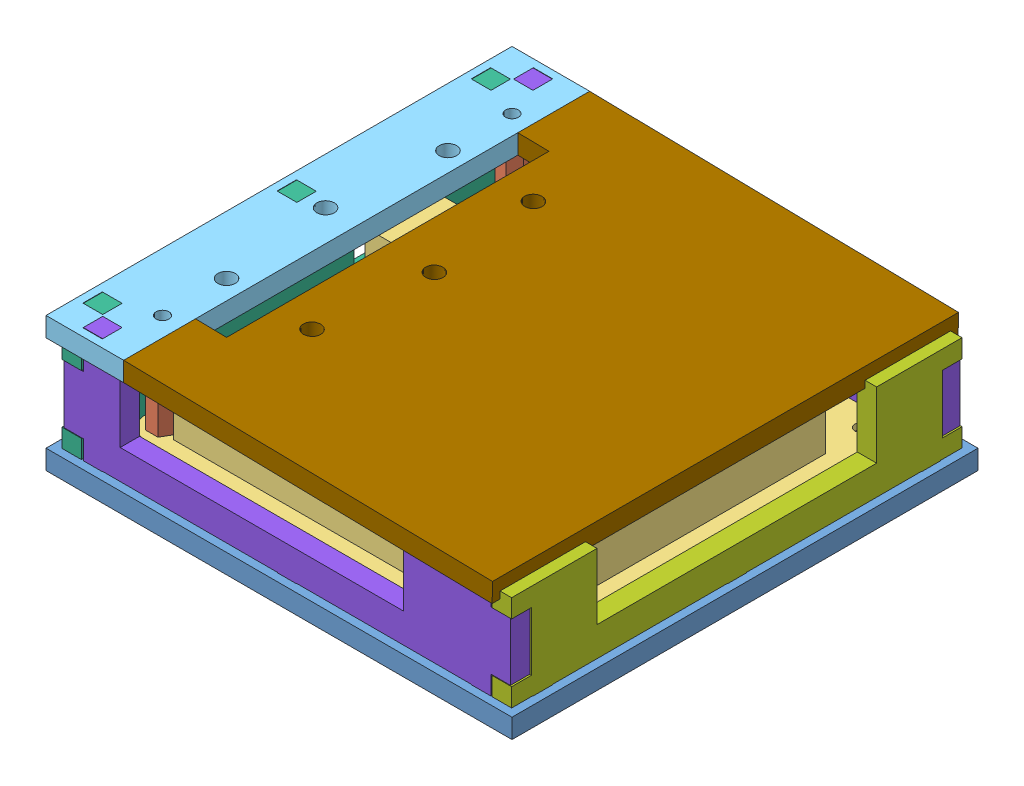
SolidWorks assembly case_assembled, configuration Default. Lengths in mm.
Overall size (120 34.6 120).
14 component instances, 9 part files, 32 mates.
Components (placement in the parent):
- base_plate-1: base_plate [Default] at (35.7404 44.7662 107.32) size (120 5 120)
- hex_pillar-1: hex_pillar [Default] at (-9.2596 54.3662 62.32) x (0.431834 0 0.901953) z (-0.901953 0 0.431834) size (6.35 20 5.5)
- pcb-1: pcb [Default] at (35.7404 52.7662 107.32) size (100 15.1 100)
- spacer-1: spacer [Default] at (-9.2596 49.7662 62.32) size (5 3 5)
- top_plate-1: top_plate [Default] at (-14.2596 74.3662 107.32) size (20 5 120)
- spacer-2: spacer [Default] at (80.7404 49.7662 62.32) size (5 3 5)
- spacer-3: spacer [Default] at (-9.2596 49.7662 152.32) size (5 3 5)
- spacer-4: spacer [Default] at (80.7404 49.7662 152.32) size (5 3 5)
- hex_pillar-2: hex_pillar [Default] at (-9.2596 54.3662 152.32) size (6.35 20 5.5)
- side_ethernet-1: side_ethernet [Default] at (-17.1596 55.9162 107.32) x (0 0 1) z (-1 0 0) size (116 34.6 5)
- side_11-20-1: side_11-20 [Default] at (88.6404 55.9162 107.32) x (0 0 -1) z (1 0 0) size (116 29.6 5)
- side_1-10_and_21-30-1: side_1-10_and_21-30 [Default] at (35.7404 55.9162 54.42) x (-1 0 0) z (0 0 -1) size (115 34.6 5)
- side_1-10_and_21-30-2: side_1-10_and_21-30 [Default] at (35.7404 55.9162 165.22) x (-1 0 0) z (0 0 -1) size (115 34.6 5)
- hinged_lid-1: hinged_lid [Default] at (43.1355 73.454 107.32) x (-0.999815 0.019223 0) z (0 0 -1) size (95 5 120)
Mates (geometry in assembly coordinates):
- Concentric1: concentric anti-aligned: cylinder of base_plate-1 through (-9.2596 49.7662 62.32) axis (0 1 0) radius 1.65; cylinder of spacer-1 through (-9.2596 52.7662 62.32) axis (0 -1 0) radius 1.6
- Coincident1: coincident anti-aligned: plane of base_plate-1 through (35.7404 49.7662 107.32) normal (0 1 0); plane of spacer-1 through (-9.2596 49.7662 62.32) normal (0 -1 0)
- Coincident2: coincident anti-aligned: plane of base_plate-1 through (35.7404 49.7662 107.32) normal (0 1 0); plane of spacer-2 through (80.7404 49.7662 62.32) normal (0 -1 0)
- Concentric2: concentric anti-aligned: circle of base_plate-1; cylinder of spacer-2 through (80.7404 52.7662 62.32) axis (0 -1 0) radius 1.6
- Coincident3: coincident anti-aligned: plane of base_plate-1 through (35.7404 49.7662 107.32) normal (0 1 0); plane of spacer-3 through (-9.2596 49.7662 152.32) normal (0 -1 0)
- Concentric3: concentric anti-aligned: cylinder of base_plate-1 through (-9.2596 49.7662 152.32) axis (0 1 0) radius 1.65; cylinder of spacer-3 through (-9.2596 52.7662 152.32) axis (0 -1 0) radius 1.6
- Coincident4: coincident anti-aligned: plane of base_plate-1 through (35.7404 49.7662 107.32) normal (0 1 0); plane of spacer-4 through (80.7404 49.7662 152.32) normal (0 -1 0)
- Concentric4: concentric anti-aligned: cylinder of base_plate-1 through (80.7404 49.7662 152.32) axis (0 1 0) radius 1.65; cylinder of spacer-4 through (80.7404 52.7662 152.32) axis (0 -1 0) radius 1.6
- Concentric5: concentric anti-aligned: cylinder of pcb-1 through (-9.2596 54.3662 62.32) axis (0 1 0) radius 1.65; cylinder of spacer-1 through (-9.2596 52.7662 62.32) axis (0 -1 0) radius 1.6
- Concentric6: concentric anti-aligned: cylinder of pcb-1 through (-9.2596 54.3662 152.32) axis (0 1 0) radius 1.65; cylinder of spacer-3 through (-9.2596 52.7662 152.32) axis (0 -1 0) radius 1.6
- Coincident5: coincident anti-aligned: plane of pcb-1 through (35.7404 52.7662 107.32) normal (0 -1 0); plane of spacer-3 through (-9.2596 52.7662 152.32) normal (0 1 0)
- Concentric7: concentric aligned: circle of hex_pillar-1; cylinder of pcb-1 through (-9.2596 54.3662 62.32) axis (0 1 0) radius 1.65
- Coincident6: coincident anti-aligned: plane of hex_pillar-1 through (-9.2596 54.3662 62.32) normal (0 -1 0); plane of pcb-1 through (35.7404 54.3662 107.32) normal (0 1 0)
- Coincident7: coincident anti-aligned: circle of pcb-1; plane of hex_pillar-2 through (-9.2596 54.3662 152.32) normal (0 -1 0)
- Concentric8: concentric aligned: circle of pcb-1; circle of hex_pillar-2
- Concentric11: concentric anti-aligned: circle of top_plate-1; cylinder of hex_pillar-2 through (-9.2596 74.3662 152.32) axis (0 -1 0) radius 1.5
- Concentric12: concentric anti-aligned: cylinder of hex_pillar-1 through (-9.2596 74.3662 62.32) axis (0 -1 0) radius 1.5; cylinder of top_plate-1 through (-9.2596 79.3662 62.32) axis (0 1 0) radius 1.65
- Coincident10: coincident anti-aligned: plane of base_plate-1 through (-17.1596 44.7662 104.82) normal (-1 0 0); plane of side_ethernet-1 through (-17.1596 55.9162 107.32) normal (1 0 0)
- Coincident11: coincident anti-aligned: plane of base_plate-1 through (-22.2596 44.7662 104.82) normal (0 0 1); plane of side_ethernet-1 through (-22.1596 44.7662 104.82) normal (0 0 -1)
- Coincident12: coincident anti-aligned: plane of base_plate-1 through (35.7404 49.7662 107.32) normal (0 1 0); plane of side_ethernet-1 through (-22.1596 49.7662 49.32) normal (0 -1 0)
- Coincident15: coincident anti-aligned: plane of base_plate-1 through (88.6404 44.7662 104.82) normal (0 0 1); plane of side_11-20-1 through (93.6404 44.7662 104.82) normal (0 0 -1)
- Coincident16: coincident anti-aligned: plane of base_plate-1 through (88.6404 44.7662 104.82) normal (1 0 0); plane of side_11-20-1 through (88.6404 55.9162 107.32) normal (-1 0 0)
- Coincident17: coincident anti-aligned: plane of base_plate-1 through (35.7404 49.7662 107.32) normal (0 1 0); plane of side_11-20-1 through (93.6404 49.7662 165.32) normal (0 -1 0)
- Coincident18: coincident anti-aligned: plane of base_plate-1 through (33.2404 44.7662 54.42) normal (0 0 -1); plane of side_1-10_and_21-30-1 through (35.7404 55.9162 54.42) normal (0 0 1)
- Coincident19: coincident anti-aligned: plane of base_plate-1 through (35.7404 49.7662 107.32) normal (0 1 0); plane of side_1-10_and_21-30-1 through (88.2404 49.7662 49.42) normal (0 -1 0)
- Coincident20: coincident anti-aligned: plane of base_plate-1 through (88.2404 44.7662 49.32) normal (-1 0 0); plane of side_1-10_and_21-30-1 through (88.2404 49.7662 49.42) normal (1 0 0)
- Coincident21: coincident anti-aligned: plane of base_plate-1 through (33.2404 44.7662 160.22) normal (0 0 1); plane of side_1-10_and_21-30-2 through (35.7404 55.9162 160.22) normal (0 0 -1)
- Coincident22: coincident anti-aligned: plane of base_plate-1 through (35.7404 49.7662 107.32) normal (0 1 0); plane of side_1-10_and_21-30-2 through (88.2404 49.7662 160.22) normal (0 -1 0)
- Coincident23: coincident anti-aligned: plane of base_plate-1 through (88.2404 44.7662 160.22) normal (-1 0 0); plane of side_1-10_and_21-30-2 through (88.2404 49.7662 160.22) normal (1 0 0)
- Coincident26: coincident anti-aligned: plane of top_plate-1 through (-14.2596 74.3662 107.32) normal (0 -1 0); plane of side_ethernet-1 through (-22.1596 74.3662 49.32) normal (0 1 0)
- Coincident30: coincident anti-aligned: line of top_plate-1 through (-4.2596 79.3662 167.32) axis (0 0 -1); line of hinged_lid-1 through (-4.2596 79.3662 47.32) axis (0 0 1)
- Coincident31: coincident aligned: plane of top_plate-1 through (-24.2596 79.3662 47.32) normal (0 0 -1); plane of hinged_lid-1 through (90.7228 77.54 47.32) normal (0 0 -1)
